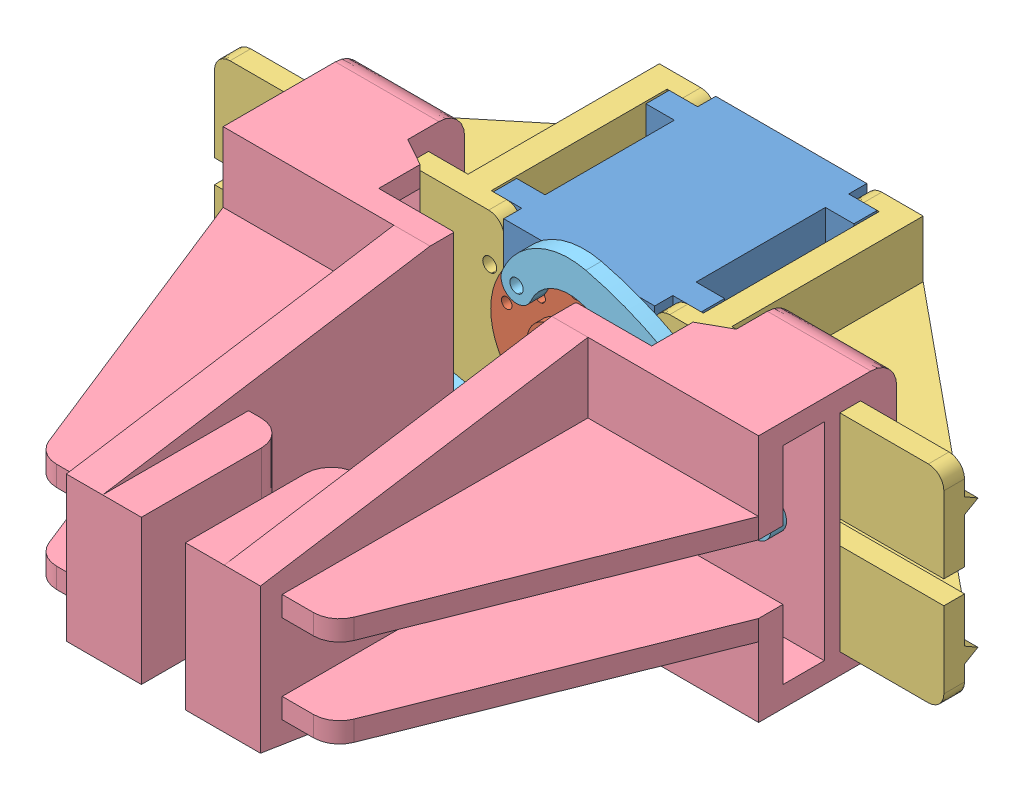
SolidWorks assembly 어셈블리3(gripper prototype, configuration 기본. Lengths in mm.
Overall size (141 71.2 121).
8 component instances, 5 part files, 16 mates.
Components (placement in the parent):
- 파트1(motor-2: 파트1(motor [기본] at (-27.5911 16.068 39.2984) size (40.2 61.1 45.7)
- 파트10(베어링-2: 파트10(베어링 [기본] at (-33.3043 7.3694 63.0984) x (-0.528213 0.849112 0) z (0 0 -1) size (27.6 27.6 5.1)
- 파트12(gripper base-3: 파트12(gripper base [기본] at (13.0089 37.168 59.7984) size (56 40 41)
- 파트12(gripper base-4: 파트12(gripper base [기본] at (-27.9911 77.168 59.7984) x (-1 0 0) z (0 0 1) size (56 40 41)
- 파트13(gripper finger prototype-3: 파트13(gripper finger prototype [기본] at (2.8937 33.168 138.7984) size (47.5 48 90)
- 파트13(gripper finger prototype-4: 파트13(gripper finger prototype [기본] at (-20.6249 81.168 138.7984) x (-1 0 0) z (0 0 1) size (47.5 48 90)
- 파트14(gripper pin prototype-3: 파트14(gripper pin prototype [기본] at (-9.5227 73.3226 63.0984) x (0.942759 -0.333474 0) z (0 0 1) size (55 16.53 3)
- 파트14(gripper pin prototype-4: 파트14(gripper pin prototype [기본] at (-5.3528 53.9171 63.0984) x (-0.998859 0.04776 0) z (0 0 1) size (55 16.53 3)
Mates (geometry in assembly coordinates):
- 동심7: concentric anti-aligned: cylinder of 파트1(motor-2 through (-7.4911 64.168 63.4984) axis (0 0 -1) radius 3.95; cylinder of 파트10(베어링-2 through (-7.4911 64.168 59.7984) axis (0 0 1) radius 4.5
- 일치16: coincident anti-aligned: plane of 파트1(motor-2 through (-27.5911 16.068 59.7984) normal (0 0 1); plane of 파트10(베어링-2 through (-33.3043 7.3694 59.7984) normal (0 0 -1)
- 일치17: coincident aligned: circle of 파트1(motor-2; circle of 파트12(gripper base-3
- 일치21: coincident aligned: circle of 파트1(motor-2; circle of 파트12(gripper base-3
- 일치23: coincident aligned: circle of 파트1(motor-2; circle of 파트12(gripper base-4
- 일치24: coincident aligned: circle of 파트1(motor-2; circle of 파트12(gripper base-4
- 일치25: coincident anti-aligned: line of 파트12(gripper base-3 through (63.0089 69.668 53.2003) axis (-1 0 0); line of 파트13(gripper finger prototype-3 through (22.8937 69.668 53.2003) axis (1 0 0)
- 일치26: coincident anti-aligned: line of 파트12(gripper base-3 through (63.0089 44.668 53.2003) axis (-1 0 0); line of 파트13(gripper finger prototype-3 through (22.8937 44.668 53.2003) axis (1 0 0)
- 일치27: coincident anti-aligned: line of 파트12(gripper base-4 through (-77.9911 69.668 53.2003) axis (1 0 0); line of 파트13(gripper finger prototype-4 through (-40.6249 69.668 53.2003) axis (-1 0 0)
- 일치28: coincident anti-aligned: line of 파트12(gripper base-4 through (-77.9911 44.668 53.2003) axis (1 0 0); line of 파트13(gripper finger prototype-4 through (-40.6249 44.668 53.2003) axis (-1 0 0)
- 동심8: concentric anti-aligned: circle of 파트10(베어링-2; circle of 파트14(gripper pin prototype-3
- 동심9: concentric anti-aligned: circle of 파트13(gripper finger prototype-3; circle of 파트14(gripper pin prototype-3
- 일치29: coincident anti-aligned: plane of 파트10(베어링-2 through (-33.3043 7.3694 63.0984) normal (0 0 1); plane of 파트14(gripper pin prototype-3 through (9.3857 40.5075 63.0984) normal (0 0 -1)
- 동심10: concentric anti-aligned: circle of 파트10(베어링-2; circle of 파트14(gripper pin prototype-4
- 동심11: concentric anti-aligned: circle of 파트13(gripper finger prototype-4; circle of 파트14(gripper pin prototype-4
- 일치30: coincident anti-aligned: plane of 파트10(베어링-2 through (-33.3043 7.3694 63.0984) normal (0 0 1); plane of 파트14(gripper pin prototype-4 through (-32.9127 79.8942 63.0984) normal (0 0 -1)
